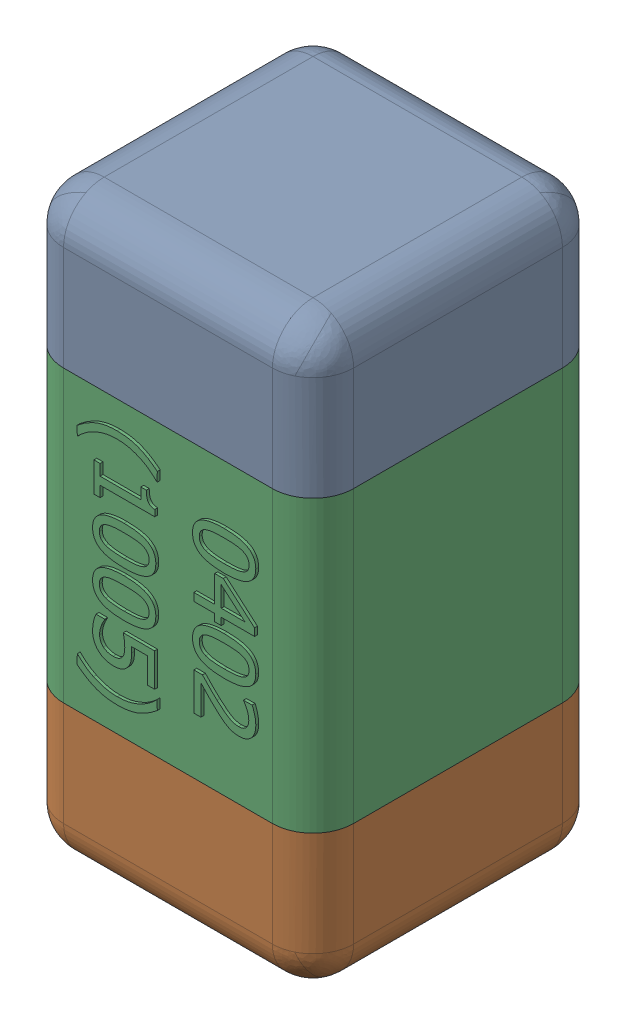
SolidWorks assembly C39, configuration Standard. Lengths in mm.
Overall size (0.51 1.01 0.51).
4 component instances, 3 part files, 0 mates.
Components (placement in the parent):
- C39-subassembly-1-1: C39-subassembly-1 [Standard] at (-15.4 17.0999 0) x (0 -1 0) z (0 0 1) size (1.01 0.51 0.51)
  - User Library-0402_Cap-1: User Library-0402_Cap [Standard] at origin size (0.26 0.51 0.51)
  - User Library-0402_Cap-1-1: User Library-0402_Cap-1 [Standard] at origin size (0.26 0.5 0.51)
  - User Library-0402_Cap-2-1: User Library-0402_Cap-2 [Standard] at origin size (0.5 0.5 0.51)
